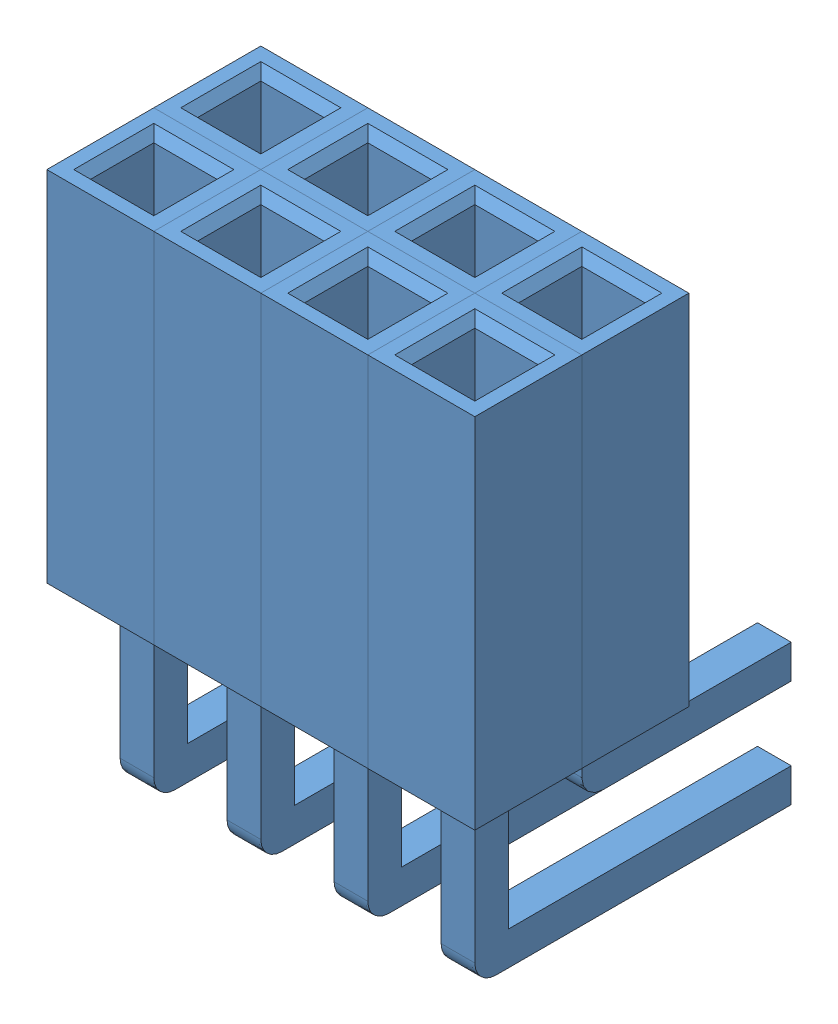
SolidWorks assembly pbd2x4, configuration По умолчанию. Lengths in mm.
Overall size (10.16 12.6 8.58).
8 component instances, 1 part files, 21 mates.
Components (placement in the parent):
- pbs1-1: pbs1 [По умолчанию] at (-3.1437 -1.4395 4.583) size (2.54 10.06 6.04)
- pbs1-2: pbs1 [По умолчанию] at (-0.6037 -1.4395 4.583) size (2.54 10.06 6.04)
- pbs1-3: pbs1 [По умолчанию] at (1.9363 -1.4395 4.583) size (2.54 10.06 6.04)
- pbs1-4: pbs1 [dowble] at (-3.1437 -1.4395 7.123) size (2.54 12.6 8.58)
- pbs1-5: pbs1 [dowble] at (-0.6037 -1.4395 7.123) size (2.54 12.6 8.58)
- pbs1-6: pbs1 [dowble] at (1.9363 -1.4395 7.123) size (2.54 12.6 8.58)
- pbs1-7: pbs1 [По умолчанию] at (4.4763 -1.4395 4.583) size (2.54 10.06 6.04)
- pbs1-8: pbs1 [dowble] at (4.4763 -1.4395 7.123) size (2.54 12.6 8.58)
Mates (geometry in assembly coordinates):
- Совпадение1: coincident anti-aligned: plane of pbs1-1 through (-0.6037 7.0605 4.583) normal (1 0 0); plane of pbs1-2 through (-0.6037 7.0605 4.583) normal (-1 0 0)
- Совпадение2: coincident aligned: plane of pbs1-1 through (-3.1437 7.0605 4.583) normal (0 1 0); plane of pbs1-2 through (-0.6037 7.0605 4.583) normal (0 1 0)
- Совпадение3: coincident aligned: plane of pbs1-1 through (-3.1437 7.0605 2.043) normal (0 0 -1); plane of pbs1-2 through (-0.6037 7.0605 2.043) normal (0 0 -1)
- Совпадение4: coincident anti-aligned: plane of pbs1-2 through (1.9363 7.0605 4.583) normal (1 0 0); plane of pbs1-3 through (1.9363 7.0605 4.583) normal (-1 0 0)
- Совпадение5: coincident aligned: plane of pbs1-2 through (-0.6037 7.0605 4.583) normal (0 1 0); plane of pbs1-3 through (1.9363 7.0605 4.583) normal (0 1 0)
- Совпадение6: coincident aligned: plane of pbs1-2 through (-0.6037 7.0605 2.043) normal (0 0 -1); plane of pbs1-3 through (1.9363 7.0605 2.043) normal (0 0 -1)
- Совпадение7: coincident anti-aligned: plane of pbs1-1 through (-3.1437 7.0605 4.583) normal (0 0 1); plane of pbs1-4 through (-3.1437 7.0605 4.583) normal (0 0 -1)
- Совпадение8: coincident aligned: plane of pbs1-1 through (-3.1437 7.0605 4.583) normal (-1 0 0); plane of pbs1-4 through (-3.1437 7.0605 7.123) normal (-1 0 0)
- Совпадение9: coincident aligned: plane of pbs1-1 through (-3.1437 7.0605 4.583) normal (0 1 0); plane of pbs1-4 through (-3.1437 7.0605 7.123) normal (0 1 0)
- Совпадение10: coincident anti-aligned: plane of pbs1-2 through (-0.6037 7.0605 4.583) normal (0 0 1); plane of pbs1-5 through (-0.6037 7.0605 4.583) normal (0 0 -1)
- Совпадение11: coincident anti-aligned: plane of pbs1-4 through (-0.6037 7.0605 7.123) normal (1 0 0); plane of pbs1-5 through (-0.6037 7.0605 7.123) normal (-1 0 0)
- Совпадение12: coincident aligned: plane of pbs1-2 through (-0.6037 7.0605 4.583) normal (0 1 0); plane of pbs1-5 through (-0.6037 7.0605 7.123) normal (0 1 0)
- Совпадение13: coincident anti-aligned: plane of pbs1-3 through (1.9363 7.0605 4.583) normal (0 0 1); plane of pbs1-6 through (1.9363 7.0605 4.583) normal (0 0 -1)
- Совпадение14: coincident anti-aligned: plane of pbs1-5 through (1.9363 7.0605 7.123) normal (1 0 0); plane of pbs1-6 through (1.9363 7.0605 7.123) normal (-1 0 0)
- Совпадение15: coincident aligned: plane of pbs1-3 through (1.9363 7.0605 4.583) normal (0 1 0); plane of pbs1-6 through (1.9363 7.0605 7.123) normal (0 1 0)
- Совпадение16: coincident anti-aligned: plane of pbs1-3 through (4.4763 7.0605 4.583) normal (1 0 0); plane of pbs1-7 through (4.4763 7.0605 4.583) normal (-1 0 0)
- Совпадение17: coincident aligned: plane of pbs1-3 through (1.9363 7.0605 2.043) normal (0 0 -1); plane of pbs1-7 through (4.4763 7.0605 2.043) normal (0 0 -1)
- Совпадение18: coincident aligned: plane of pbs1-3 through (1.9363 7.0605 4.583) normal (0 1 0); plane of pbs1-7 through (4.4763 7.0605 4.583) normal (0 1 0)
- Совпадение19: coincident anti-aligned: plane of pbs1-6 through (4.4763 7.0605 7.123) normal (1 0 0); plane of pbs1-8 through (4.4763 7.0605 7.123) normal (-1 0 0)
- Совпадение20: coincident aligned: plane of pbs1-6 through (1.9363 7.0605 7.123) normal (0 0 1); plane of pbs1-8 through (4.4763 7.0605 7.123) normal (0 0 1)
- Совпадение21: coincident aligned: plane of pbs1-6 through (1.9363 7.0605 7.123) normal (0 1 0); plane of pbs1-8 through (4.4763 7.0605 7.123) normal (0 1 0)
